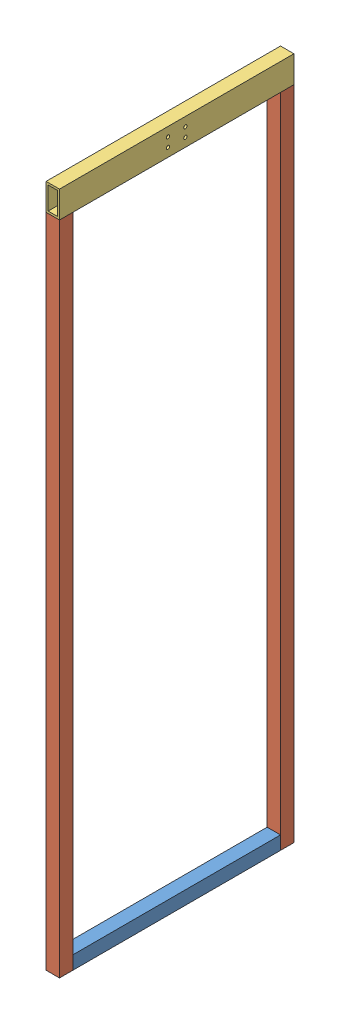
SolidWorks assembly 010113_frame_cylinder_side, configuration Default. Lengths in mm.
Overall size (40 2040 700).
4 component instances, 3 part files, 6 mates.
Components (placement in the parent):
- 010101_ST_40x4x620-1: 010101_ST_40x4x620 [Default] at (466.5776 568.0253 186.9825) size (40 40 620)
- 010102_ST_40x4x1960-1: 010102_ST_40x4x1960 [Default] at (466.5776 2508.0253 826.9825) x (-1 0 0) z (0 -1 0) size (40 40 1960)
- 010110_RT_80x40x6.3x700_drilled-1: 010110_RT_80x40x6.3x700_drilled [Default] at (466.5776 2548.0253 496.9825) size (40 80 700)
- 010102_ST_40x4x1960-2: 010102_ST_40x4x1960 [Default] at (466.5776 548.0253 166.9825) x (-1 0 0) z (0 1 0) size (40 40 1960)
Mates (geometry in assembly coordinates):
- Coincident1: coincident aligned: plane of 010101_ST_40x4x1000-1 through (446.5776 548.0253 186.9825) normal (0 -1 0); plane of 010102_ST_40x4x2140-1 through (466.5776 548.0253 826.9825) normal (0 -1 0)
- Coincident2: coincident aligned: plane of 010101_ST_40x4x1000-1 through (486.5776 588.0253 186.9825) normal (1 0 0); plane of 010102_ST_40x4x2140-1 through (486.5776 2508.0253 806.9825) normal (1 0 0)
- Coincident3: coincident: line of 010101_ST_40x4x1000-1 through (486.5776 588.0253 806.9825) axis (-1 0 0); plane of 010102_ST_40x4x2140-1 through (486.5776 2508.0253 806.9825) normal (0 0 -1)
- Coincident4: coincident aligned: plane of 010102_ST_40x4x2140-1 through (486.5776 2508.0253 806.9825) normal (1 0 0); plane of 010110_RT_80x40x6.3x1080_drilled-1 through (486.5776 2588.0253 846.9825) normal (1 0 0)
- Coincident5: coincident aligned: plane of 010102_ST_40x4x2140-1 through (486.5776 2508.0253 846.9825) normal (0 0 1); plane of 010110_RT_80x40x6.3x1080_drilled-1 through (466.5776 2548.0253 846.9825) normal (0 0 1)
- Coincident6: coincident anti-aligned: plane of 010102_ST_40x4x2140-1 through (466.5776 2508.0253 826.9825) normal (0 1 0); plane of 010110_RT_80x40x6.3x1080_drilled-1 through (446.5776 2508.0253 846.9825) normal (0 -1 0)
